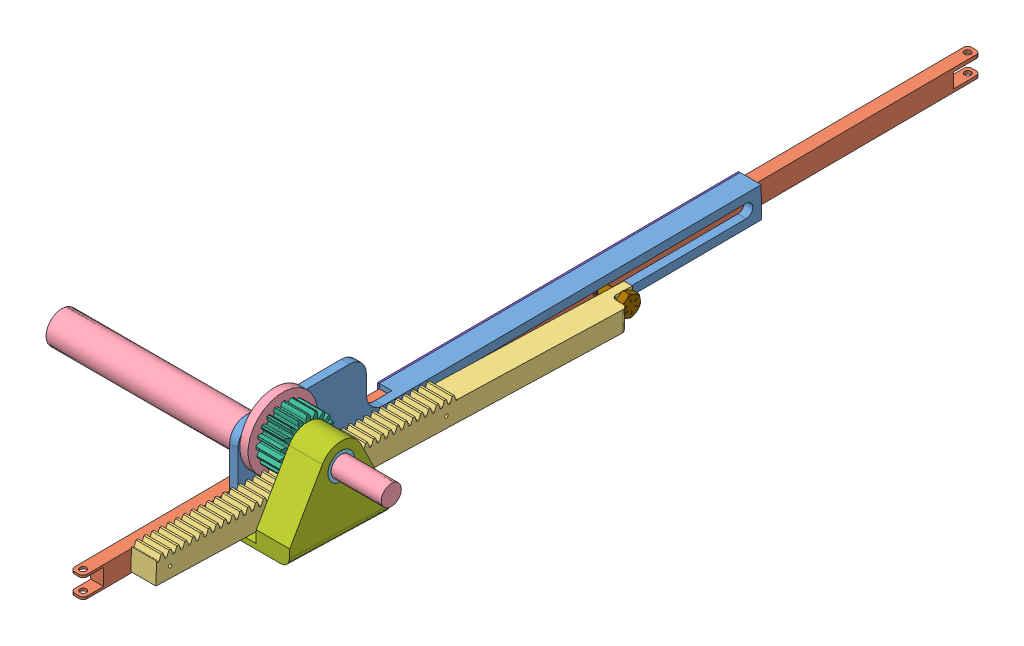
SolidWorks assembly ProgressiveSteering, configuration Default. Lengths in mm.
Overall size (197 187.8 537.27).
10 component instances, 10 part files, 23 mates.
Components (placement in the parent):
- SI_sdpsi_s1268z-024s040-2: SI_sdpsi_s1268z-024s040 [Default] at (1.5875 -10.9322 -6.4635) x (1 0 0) z (0 0.508936 -0.860805)
- slot v2.2-2: slot v2.2 [Default] at (-16.3313 -50.6873 -22.7502) x (0 -0.006116 0.999981) z (-1 0 0) size (313.22 50 12.62)
- steering bar-1: steering bar [Default] at (-21.3313 -49.8568 298.2831) x (-1 0 0) z (0 0.006116 -0.999981) size (8.06 12.7 537.2)
- KHK-US_SRAF1_5-1000.stp-1: KHK-US_SRAF1_5-1000.stp [Default] at (-3.8313 -23.8651 678.9681) x (-1 0 0) z (0 -0.030174 -0.999545) size (16.43 15 295)
- adapterplate(unfinished)-1: adapterplate(unfinished) [Default] at (-11.3313 -12.5858 268.823) x (0 -0.02013 -0.999797) z (1 0 0) size (184.13 184.13 197)
- 6995N126_Iron-Copper High-Load Oil-Embedded Sleeve Bearing-1: 6995N126_Iron-Copper High-Load Oil-Embedded Sleeve Bearing [6995N126] at (13.6687 -12.5858 268.823) x (0 0.886408 0.462904) z (-1 0 0) size (16 16 20)
- KHK-US_SSA1_5-20J12.stp-1: KHK-US_SSA1_5-20J12.stp [Default] at (-3.8313 -12.5858 268.823) x (-1 0 0) z (0 -0.999797 0.02013) size (15 33 33)
- slider-2: slider [Default] at (3.6687 -12.5858 268.823) x (0 -0.030174 -0.999545) z (1 0 0) size (60 51.5 35)
- slot plate-1: slot plate [Default] at (-29.9513 -50.3955 -31.3797) x (0 0.006116 -0.999981) z (1 0 0) size (216.04 18.29 1)
- 92620A540_Zinc Yellow-Chromate Plated Hex Head Screw-1: 92620A540_Zinc Yellow-Chromate Plated Hex Head Screw [92620A540] at (-13.5935 -42.1088 69.7262) x (-1 0 0) z (0 -0.910337 0.413867) size (23.81 12.83 11.11)
Mates (geometry in assembly coordinates):
- Distance6: distance = 3.175 mm aligned: plane of slot-1 through (7.0485 -3.175 -260.805) normal (0 1 0)
- Distance8: distance = 12.7 mm: plane of assembly through (0 0 0) normal (1 0 0); plane of assembly; plane of slot-1 through (7.0485 -34.2791 -85.7379) normal (1 0 0)
- Distance9: distance = 29.5 mm: line of KHK-US_SRAF1_5-1000.stp-1 through (3.6687 -39.3536 359.7752) axis (0 -0.030174 -0.999545); cylinder of adapterplate(unfinished)-1 through (3.6687 -12.5858 268.823) axis (-1 0 0) radius 6
- Concentric17: concentric anti-aligned: cylinder of adapterplate(unfinished)-1 through (3.6687 -12.5858 268.823) axis (-1 0 0) radius 6; cylinder of 6995N126_Iron-Copper High-Load Oil-Embedded Sleeve Bearing-1 through (3.6687 -12.5858 268.823) axis (1 0 0) radius 8
- Concentric18: concentric anti-aligned: cylinder of 6995N126_Iron-Copper High-Load Oil-Embedded Sleeve Bearing-1 through (3.6687 -12.5858 268.823) axis (1 0 0) radius 8; cylinder of slider-2 through (23.6687 -12.5858 268.823) axis (-1 0 0) radius 8
- Coincident48: coincident anti-aligned: circle of 6995N126_Iron-Copper High-Load Oil-Embedded Sleeve Bearing-1; circle of slider-2
- Coincident50: coincident anti-aligned: plane of KHK-US_SRAF1_5-1000.stp-1 through (3.6687 -2.9454 1178.0792) normal (1 0 0); plane of slider-2 through (3.6687 -12.5858 268.823) normal (-1 0 0)
- Coincident53: coincident aligned: circle of adapterplate(unfinished)-1; circle of KHK-US_SSA1_5-20J12.stp-1
- Coincident54: coincident anti-aligned: plane of adapterplate(unfinished)-1 through (3.6687 -6.8898 270.7087) normal (0 0.02013 0.999797); plane of KHK-US_SSA1_5-20J12.stp-1 through (-12.8313 -6.8898 270.7087) normal (0 -0.02013 -0.999797)
- Coincident55: coincident aligned: plane of KHK-US_SRAF1_5-1000.stp-1 through (3.6687 -2.9454 1178.0792) normal (1 0 0); plane of KHK-US_SSA1_5-20J12.stp-1 through (3.6687 -12.5858 268.823) normal (1 0 0)
- Parallel3: parallel anti-aligned: plane of KHK-US_SRAF1_5-1000.stp-1 through (3.6687 -14.64 1178.4322) normal (0 -0.999545 0.030174); plane of slider-2 through (-11.3313 -48.9749 239.9078) normal (0 0.999545 -0.030174)
- Concentric21: concentric aligned: circle of slot v2.2-2; circle of adapterplate(unfinished)-1
- Coincident56: coincident anti-aligned: plane of slot v2.2-2 through (-16.3313 -50.6873 -22.7502) normal (1 0 0); plane of adapterplate(unfinished)-1 through (-16.3313 -12.5858 268.823) normal (-1 0 0)
- Coincident57: coincident anti-aligned: plane of slot v2.2-2 through (-21.3313 -50.6873 -22.7502) normal (-1 0 0); plane of steering bar-1 through (-21.3313 -47.0605 -158.9083) normal (1 0 0)
- Coincident58: coincident anti-aligned: plane of slot v2.2-2 through (-28.9513 -35.1936 -22.6555) normal (0 -0.999981 -0.006116); plane of steering bar-1 through (-21.3313 -34.3608 -158.8307) normal (0 0.999981 0.006116)
- Coincident62: coincident anti-aligned: circle of slot v2.2-2; circle of slot plate-1
- Parallel5: parallel aligned: plane of slot v2.2-2 through (-21.3313 -32.3997 -22.6384) normal (0 0.999981 0.006116); plane of slot plate-1 through (-28.9513 -32.3489 -31.2694) normal (0 0.999981 0.006116)
- Concentric23: concentric aligned: circle of KHK-US_SRAF1_5-1000.stp-1; circle of 92620A540_Zinc Yellow-Chromate Plated Hex Head Screw-1
- Concentric24: concentric anti-aligned: circle of steering bar-1; circle of 92620A540_Zinc Yellow-Chromate Plated Hex Head Screw-1
- Slot6: slot anti-aligned: cylinder of 92620A540_Zinc Yellow-Chromate Plated Hex Head Screw-1 through (-6.2513 -42.1088 69.7262) axis (-1 0 0) radius 3.175; plane of slot v2.2-2 through (-21.3313 -45.5434 -22.7188) normal (0 0.999981 0.006116); cylinder of slot v2.2-2 through (-21.3313 -41.599 -13.6145) axis (1 0 0) radius 4
- Coincident65: coincident anti-aligned: plane of KHK-US_SRAF1_5-1000.stp-1 through (-6.2513 -48.255 64.9095) normal (1 0 0); plane of 92620A540_Zinc Yellow-Chromate Plated Hex Head Screw-1 through (-6.2513 -45.8392 74.946) normal (-1 0 0)
- RackPinionMate1: rack pinion = 30 mm: line of KHK-US_SRAF1_5-1000.stp-1 through (-11.3313 -34.7611 64.5021) axis (0 0.030174 0.999545); circle of KHK-US_SSA1_5-20J12.stp-1
- Perpendicular1: perpendicular: line of slot v2.2-2 through (-16.3313 -50.6873 -22.7502) axis (0 -0.006116 0.999981); line of adapterplate(unfinished)-1 through (-143.3313 -16.3577 269.2323) axis (0 -0.999981 -0.006116)
